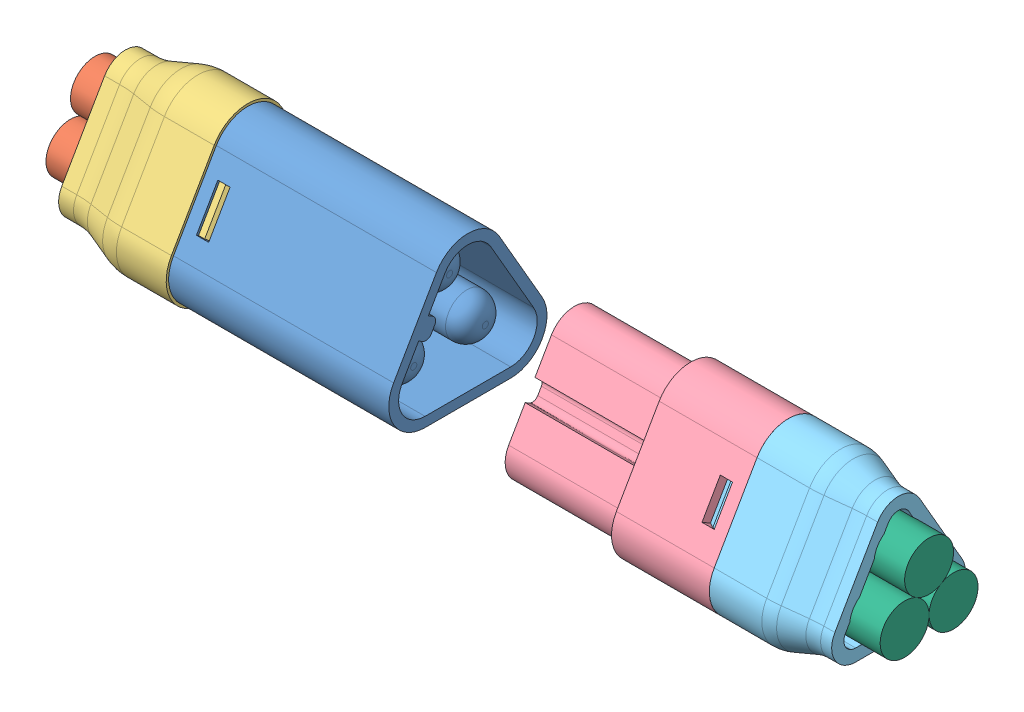
SolidWorks assembly MT60, configuration По умолчанию. Lengths in mm.
Overall size (68.21 12.4 13.34).
8 component instances, 6 part files, 2 mates.
Components (placement in the parent):
- mt60 male-1: mt60 male [Default] at origin size (30.5 12.4 13.34)
  - Copy of Папа^mt60 male-1: Copy of Папа^mt60 male [По умолчанию] at origin size (20 12 12.94) (virtual)
  - Copy of Провода^mt60 male-1: Copy of Провода^mt60 male [По умолчанию] at (-18.5 0 0) x (0 0 1) z (-1 0 0) size (7.99 7.46 9.5) (virtual)
  - Copy of Колпчек^mt60 male-1: Copy of Колпчек^mt60 male [По умолчанию] at (-3.5 0 0) x (0 0 1) z (-1 0 0) size (13.34 12.4 15) (virtual)
- mt60 female-1: mt60 female [Default] at origin size (29 12 12.94)
  - Copy of Мама^mt60 female-1: Copy of Мама^mt60 female [По умолчанию] at (18.214 0 0) x (0 0 -1) z (1 0 0) size (12.94 12 20) (virtual)
  - Copy of Колпачек 2^mt60 female-1: Copy of Колпачек 2^mt60 female [По умолчанию] at (35.714 0 0) x (0 0 -1) z (1 0 0) size (12.94 12 13) (virtual)
  - Copy of Деталь11^mt60 female-1: Copy of Деталь11^mt60 female [По умолчанию] at (44.714 0 0) x (0 0 -1) z (1 0 0) size (8 7.46 6.5) (virtual)
Mates (geometry in assembly coordinates):
- Coincident3: coincident anti-aligned: plane of mt60 male^MT60-1/Copy of Папа^mt60 male_MT60-1 through (9.5 10.1155 -1.8783) normal (0 -0.5 0.866025); plane of Assem2^MT60-1/Copy of Мама^Assem2_MT60-1 through (27.714 4.0534 -5.3783) normal (0 0.5 -0.866025)
- Coincident4: coincident anti-aligned: plane of mt60 male^MT60-1/Copy of Папа^mt60 male_MT60-1 through (9.5 0.8 -3.5) normal (0 1 0); plane of Assem2^MT60-1/Copy of Мама^Assem2_MT60-1 through (27.714 0.8 3.5) normal (0 -1 0)
